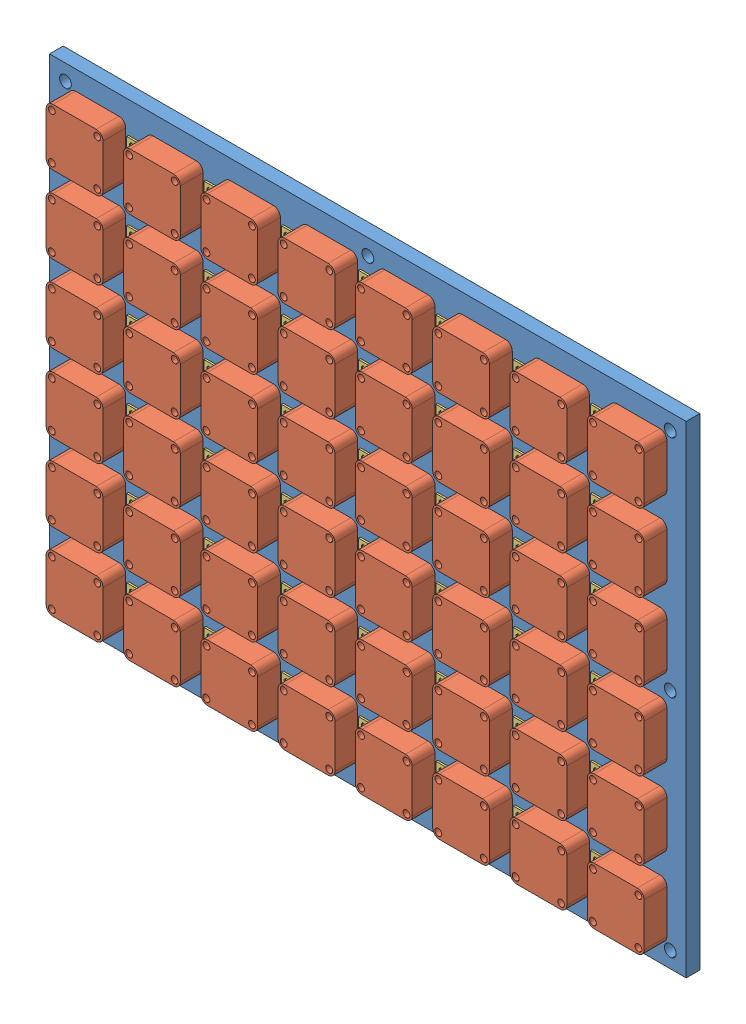
SolidWorks assembly plate_assembly, configuration Default. Lengths in mm.
Overall size (280 212 16.95).
134 component instances, 4 part files, 11 mates.
Components (placement in the parent):
- plate-1: plate [Default] at (3.9208 5.1033 -0.2161) size (280 212 6)
- Fan-1: Fan [Default] at (-115.0792 40.1033 15.7839) size (25 25 10)
- XHP-2-1: XHP-2 [Default] at (-101.3792 93.7533 2.7139) x (0 1 0) z (1 0 0) size (7.3 7.75 5.7)
- XHP-2-2: XHP-2 [Default] at (-101.3792 86.4533 2.7139) x (0 1 0) z (1 0 0) size (7.3 7.75 5.7)
- Fan-2: Fan [Default] at (-115.0792 74.1033 15.7839) size (25 25 10)
- Fan-3: Fan [Default] at (-115.0792 108.1033 15.7839) size (25 25 10)
- Fan-4: Fan [Default] at (-115.0792 142.1033 15.7839) size (25 25 10)
- Fan-5: Fan [Default] at (-115.0792 176.1033 15.7839) size (25 25 10)
- Fan-6: Fan [Default] at (-115.0792 210.1033 15.7839) size (25 25 10)
- Fan-7: Fan [Default] at (-81.0792 40.1033 15.7839) size (25 25 10)
- Fan-8: Fan [Default] at (-81.0792 74.1033 15.7839) size (25 25 10)
- Fan-9: Fan [Default] at (-81.0792 108.1033 15.7839) size (25 25 10)
- Fan-10: Fan [Default] at (-81.0792 142.1033 15.7839) size (25 25 10)
- Fan-11: Fan [Default] at (-81.0792 176.1033 15.7839) size (25 25 10)
- Fan-12: Fan [Default] at (-81.0792 210.1033 15.7839) size (25 25 10)
- Fan-13: Fan [Default] at (-47.0792 40.1033 15.7839) size (25 25 10)
- Fan-14: Fan [Default] at (-47.0792 74.1033 15.7839) size (25 25 10)
- Fan-15: Fan [Default] at (-47.0792 108.1033 15.7839) size (25 25 10)
- Fan-16: Fan [Default] at (-47.0792 142.1033 15.7839) size (25 25 10)
- Fan-17: Fan [Default] at (-47.0792 176.1033 15.7839) size (25 25 10)
- Fan-18: Fan [Default] at (-47.0792 210.1033 15.7839) size (25 25 10)
- Fan-19: Fan [Default] at (-13.0792 40.1033 15.7839) size (25 25 10)
- Fan-20: Fan [Default] at (-13.0792 74.1033 15.7839) size (25 25 10)
- Fan-21: Fan [Default] at (-13.0792 108.1033 15.7839) size (25 25 10)
- Fan-22: Fan [Default] at (-13.0792 142.1033 15.7839) size (25 25 10)
- Fan-23: Fan [Default] at (-13.0792 176.1033 15.7839) size (25 25 10)
- Fan-24: Fan [Default] at (-13.0792 210.1033 15.7839) size (25 25 10)
- Fan-25: Fan [Default] at (20.9208 40.1033 15.7839) size (25 25 10)
- Fan-26: Fan [Default] at (20.9208 74.1033 15.7839) size (25 25 10)
- Fan-27: Fan [Default] at (20.9208 108.1033 15.7839) size (25 25 10)
- Fan-28: Fan [Default] at (20.9208 142.1033 15.7839) size (25 25 10)
- Fan-29: Fan [Default] at (20.9208 176.1033 15.7839) size (25 25 10)
- Fan-30: Fan [Default] at (20.9208 210.1033 15.7839) size (25 25 10)
- Fan-31: Fan [Default] at (54.9208 40.1033 15.7839) size (25 25 10)
- Fan-32: Fan [Default] at (54.9208 74.1033 15.7839) size (25 25 10)
- Fan-33: Fan [Default] at (54.9208 108.1033 15.7839) size (25 25 10)
- Fan-34: Fan [Default] at (54.9208 142.1033 15.7839) size (25 25 10)
- Fan-35: Fan [Default] at (54.9208 176.1033 15.7839) size (25 25 10)
- Fan-36: Fan [Default] at (54.9208 210.1033 15.7839) size (25 25 10)
- Fan-37: Fan [Default] at (88.9208 40.1033 15.7839) size (25 25 10)
- Fan-38: Fan [Default] at (88.9208 74.1033 15.7839) size (25 25 10)
- Fan-39: Fan [Default] at (88.9208 108.1033 15.7839) size (25 25 10)
- Fan-40: Fan [Default] at (88.9208 142.1033 15.7839) size (25 25 10)
- Fan-41: Fan [Default] at (88.9208 176.1033 15.7839) size (25 25 10)
- Fan-42: Fan [Default] at (88.9208 210.1033 15.7839) size (25 25 10)
- Fan-43: Fan [Default] at (122.9208 40.1033 15.7839) size (25 25 10)
- Fan-44: Fan [Default] at (122.9208 74.1033 15.7839) size (25 25 10)
- Fan-45: Fan [Default] at (122.9208 108.1033 15.7839) size (25 25 10)
- Fan-46: Fan [Default] at (122.9208 142.1033 15.7839) size (25 25 10)
- Fan-47: Fan [Default] at (122.9208 176.1033 15.7839) size (25 25 10)
- Fan-48: Fan [Default] at (122.9208 210.1033 15.7839) size (25 25 10)
- Board^plate_assembly-1: Board^plate_assembly [Default] at (-14.5259 93.2281 -1.2161) (suppressed, hidden, virtual)
- XHP-2-3: XHP-2 [Default] at (-67.3792 86.4533 2.7139) x (0 1 0) z (1 0 0) size (7.3 7.75 5.7)
- XHP-2-4: XHP-2 [Default] at (-33.3792 86.4533 2.7139) x (0 1 0) z (1 0 0) size (7.3 7.75 5.7)
- XHP-2-5: XHP-2 [Default] at (0.6208 86.4533 2.7139) x (0 1 0) z (1 0 0) size (7.3 7.75 5.7)
- XHP-2-6: XHP-2 [Default] at (34.6208 86.4533 2.7139) x (0 1 0) z (1 0 0) size (7.3 7.75 5.7)
- XHP-2-7: XHP-2 [Default] at (68.6208 86.4533 2.7139) x (0 1 0) z (1 0 0) size (7.3 7.75 5.7)
- XHP-2-8: XHP-2 [Default] at (102.6208 86.4533 2.7139) x (0 1 0) z (1 0 0) size (7.3 7.75 5.7)
- XHP-2-9: XHP-2 [Default] at (-101.3792 52.4533 2.7139) x (0 1 0) z (1 0 0) size (7.3 7.75 5.7)
- XHP-2-10: XHP-2 [Default] at (-67.3792 52.4533 2.7139) x (0 1 0) z (1 0 0) size (7.3 7.75 5.7)
- XHP-2-11: XHP-2 [Default] at (-33.3792 52.4533 2.7139) x (0 1 0) z (1 0 0) size (7.3 7.75 5.7)
- XHP-2-12: XHP-2 [Default] at (0.6208 52.4533 2.7139) x (0 1 0) z (1 0 0) size (7.3 7.75 5.7)
- XHP-2-13: XHP-2 [Default] at (34.6208 52.4533 2.7139) x (0 1 0) z (1 0 0) size (7.3 7.75 5.7)
- XHP-2-14: XHP-2 [Default] at (68.6208 52.4533 2.7139) x (0 1 0) z (1 0 0) size (7.3 7.75 5.7)
- XHP-2-15: XHP-2 [Default] at (102.6208 52.4533 2.7139) x (0 1 0) z (1 0 0) size (7.3 7.75 5.7)
- XHP-2-16: XHP-2 [Default] at (-101.3792 18.4533 2.7139) x (0 1 0) z (1 0 0) size (7.3 7.75 5.7)
- XHP-2-17: XHP-2 [Default] at (-67.3792 18.4533 2.7139) x (0 1 0) z (1 0 0) size (7.3 7.75 5.7)
- XHP-2-18: XHP-2 [Default] at (-33.3792 18.4533 2.7139) x (0 1 0) z (1 0 0) size (7.3 7.75 5.7)
- XHP-2-19: XHP-2 [Default] at (0.6208 18.4533 2.7139) x (0 1 0) z (1 0 0) size (7.3 7.75 5.7)
- XHP-2-20: XHP-2 [Default] at (34.6208 18.4533 2.7139) x (0 1 0) z (1 0 0) size (7.3 7.75 5.7)
- XHP-2-21: XHP-2 [Default] at (68.6208 18.4533 2.7139) x (0 1 0) z (1 0 0) size (7.3 7.75 5.7)
- XHP-2-22: XHP-2 [Default] at (102.6208 18.4533 2.7139) x (0 1 0) z (1 0 0) size (7.3 7.75 5.7)
- XHP-2-23: XHP-2 [Default] at (-101.3792 -15.5467 2.7139) x (0 1 0) z (1 0 0) size (7.3 7.75 5.7)
- XHP-2-24: XHP-2 [Default] at (-67.3792 -15.5467 2.7139) x (0 1 0) z (1 0 0) size (7.3 7.75 5.7)
- XHP-2-25: XHP-2 [Default] at (-33.3792 -15.5467 2.7139) x (0 1 0) z (1 0 0) size (7.3 7.75 5.7)
- XHP-2-26: XHP-2 [Default] at (0.6208 -15.5467 2.7139) x (0 1 0) z (1 0 0) size (7.3 7.75 5.7)
- XHP-2-27: XHP-2 [Default] at (34.6208 -15.5467 2.7139) x (0 1 0) z (1 0 0) size (7.3 7.75 5.7)
- XHP-2-28: XHP-2 [Default] at (68.6208 -15.5467 2.7139) x (0 1 0) z (1 0 0) size (7.3 7.75 5.7)
- XHP-2-29: XHP-2 [Default] at (102.6208 -15.5467 2.7139) x (0 1 0) z (1 0 0) size (7.3 7.75 5.7)
- XHP-2-30: XHP-2 [Default] at (-101.3792 -49.5467 2.7139) x (0 1 0) z (1 0 0) size (7.3 7.75 5.7)
- XHP-2-31: XHP-2 [Default] at (-67.3792 -49.5467 2.7139) x (0 1 0) z (1 0 0) size (7.3 7.75 5.7)
- XHP-2-32: XHP-2 [Default] at (-33.3792 -49.5467 2.7139) x (0 1 0) z (1 0 0) size (7.3 7.75 5.7)
- XHP-2-33: XHP-2 [Default] at (0.6208 -49.5467 2.7139) x (0 1 0) z (1 0 0) size (7.3 7.75 5.7)
- XHP-2-34: XHP-2 [Default] at (34.6208 -49.5467 2.7139) x (0 1 0) z (1 0 0) size (7.3 7.75 5.7)
- XHP-2-35: XHP-2 [Default] at (68.6208 -49.5467 2.7139) x (0 1 0) z (1 0 0) size (7.3 7.75 5.7)
- XHP-2-36: XHP-2 [Default] at (102.6208 -49.5467 2.7139) x (0 1 0) z (1 0 0) size (7.3 7.75 5.7)
- XHP-2-37: XHP-2 [Default] at (-101.3792 -83.5467 2.7139) x (0 1 0) z (1 0 0) size (7.3 7.75 5.7)
- XHP-2-38: XHP-2 [Default] at (-67.3792 -83.5467 2.7139) x (0 1 0) z (1 0 0) size (7.3 7.75 5.7)
- XHP-2-39: XHP-2 [Default] at (-33.3792 -83.5467 2.7139) x (0 1 0) z (1 0 0) size (7.3 7.75 5.7)
- XHP-2-40: XHP-2 [Default] at (0.6208 -83.5467 2.7139) x (0 1 0) z (1 0 0) size (7.3 7.75 5.7)
- XHP-2-41: XHP-2 [Default] at (34.6208 -83.5467 2.7139) x (0 1 0) z (1 0 0) size (7.3 7.75 5.7)
- XHP-2-42: XHP-2 [Default] at (68.6208 -83.5467 2.7139) x (0 1 0) z (1 0 0) size (7.3 7.75 5.7)
- XHP-2-43: XHP-2 [Default] at (102.6208 -83.5467 2.7139) x (0 1 0) z (1 0 0) size (7.3 7.75 5.7)
- XHP-2-44: XHP-2 [Default] at (-67.3792 93.7533 2.7139) x (0 1 0) z (1 0 0) size (7.3 7.75 5.7)
- XHP-2-45: XHP-2 [Default] at (-33.3792 93.7533 2.7139) x (0 1 0) z (1 0 0) size (7.3 7.75 5.7)
- XHP-2-46: XHP-2 [Default] at (0.6208 93.7533 2.7139) x (0 1 0) z (1 0 0) size (7.3 7.75 5.7)
- XHP-2-47: XHP-2 [Default] at (34.6208 93.7533 2.7139) x (0 1 0) z (1 0 0) size (7.3 7.75 5.7)
- XHP-2-48: XHP-2 [Default] at (68.6208 93.7533 2.7139) x (0 1 0) z (1 0 0) size (7.3 7.75 5.7)
- XHP-2-49: XHP-2 [Default] at (102.6208 93.7533 2.7139) x (0 1 0) z (1 0 0) size (7.3 7.75 5.7)
- XHP-2-50: XHP-2 [Default] at (-101.3792 59.7533 2.7139) x (0 1 0) z (1 0 0) size (7.3 7.75 5.7)
- XHP-2-51: XHP-2 [Default] at (-67.3792 59.7533 2.7139) x (0 1 0) z (1 0 0) size (7.3 7.75 5.7)
- XHP-2-52: XHP-2 [Default] at (-33.3792 59.7533 2.7139) x (0 1 0) z (1 0 0) size (7.3 7.75 5.7)
- XHP-2-53: XHP-2 [Default] at (0.6208 59.7533 2.7139) x (0 1 0) z (1 0 0) size (7.3 7.75 5.7)
- XHP-2-54: XHP-2 [Default] at (34.6208 59.7533 2.7139) x (0 1 0) z (1 0 0) size (7.3 7.75 5.7)
- XHP-2-55: XHP-2 [Default] at (68.6208 59.7533 2.7139) x (0 1 0) z (1 0 0) size (7.3 7.75 5.7)
- XHP-2-56: XHP-2 [Default] at (102.6208 59.7533 2.7139) x (0 1 0) z (1 0 0) size (7.3 7.75 5.7)
- XHP-2-57: XHP-2 [Default] at (-101.3792 25.7533 2.7139) x (0 1 0) z (1 0 0) size (7.3 7.75 5.7)
- XHP-2-58: XHP-2 [Default] at (-67.3792 25.7533 2.7139) x (0 1 0) z (1 0 0) size (7.3 7.75 5.7)
- XHP-2-59: XHP-2 [Default] at (-33.3792 25.7533 2.7139) x (0 1 0) z (1 0 0) size (7.3 7.75 5.7)
- XHP-2-60: XHP-2 [Default] at (0.6208 25.7533 2.7139) x (0 1 0) z (1 0 0) size (7.3 7.75 5.7)
- XHP-2-61: XHP-2 [Default] at (34.6208 25.7533 2.7139) x (0 1 0) z (1 0 0) size (7.3 7.75 5.7)
- XHP-2-62: XHP-2 [Default] at (68.6208 25.7533 2.7139) x (0 1 0) z (1 0 0) size (7.3 7.75 5.7)
- XHP-2-63: XHP-2 [Default] at (102.6208 25.7533 2.7139) x (0 1 0) z (1 0 0) size (7.3 7.75 5.7)
- XHP-2-64: XHP-2 [Default] at (-101.3792 -8.2467 2.7139) x (0 1 0) z (1 0 0) size (7.3 7.75 5.7)
- XHP-2-65: XHP-2 [Default] at (-67.3792 -8.2467 2.7139) x (0 1 0) z (1 0 0) size (7.3 7.75 5.7)
- XHP-2-66: XHP-2 [Default] at (-33.3792 -8.2467 2.7139) x (0 1 0) z (1 0 0) size (7.3 7.75 5.7)
- XHP-2-67: XHP-2 [Default] at (0.6208 -8.2467 2.7139) x (0 1 0) z (1 0 0) size (7.3 7.75 5.7)
- XHP-2-68: XHP-2 [Default] at (34.6208 -8.2467 2.7139) x (0 1 0) z (1 0 0) size (7.3 7.75 5.7)
- XHP-2-69: XHP-2 [Default] at (68.6208 -8.2467 2.7139) x (0 1 0) z (1 0 0) size (7.3 7.75 5.7)
- XHP-2-70: XHP-2 [Default] at (102.6208 -8.2467 2.7139) x (0 1 0) z (1 0 0) size (7.3 7.75 5.7)
- XHP-2-71: XHP-2 [Default] at (-101.3792 -42.2467 2.7139) x (0 1 0) z (1 0 0) size (7.3 7.75 5.7)
- XHP-2-72: XHP-2 [Default] at (-67.3792 -42.2467 2.7139) x (0 1 0) z (1 0 0) size (7.3 7.75 5.7)
- XHP-2-73: XHP-2 [Default] at (-33.3792 -42.2467 2.7139) x (0 1 0) z (1 0 0) size (7.3 7.75 5.7)
- XHP-2-74: XHP-2 [Default] at (0.6208 -42.2467 2.7139) x (0 1 0) z (1 0 0) size (7.3 7.75 5.7)
- XHP-2-75: XHP-2 [Default] at (34.6208 -42.2467 2.7139) x (0 1 0) z (1 0 0) size (7.3 7.75 5.7)
- XHP-2-76: XHP-2 [Default] at (68.6208 -42.2467 2.7139) x (0 1 0) z (1 0 0) size (7.3 7.75 5.7)
- XHP-2-77: XHP-2 [Default] at (102.6208 -42.2467 2.7139) x (0 1 0) z (1 0 0) size (7.3 7.75 5.7)
- XHP-2-78: XHP-2 [Default] at (-101.3792 -76.2467 2.7139) x (0 1 0) z (1 0 0) size (7.3 7.75 5.7)
- XHP-2-79: XHP-2 [Default] at (-67.3792 -76.2467 2.7139) x (0 1 0) z (1 0 0) size (7.3 7.75 5.7)
- XHP-2-80: XHP-2 [Default] at (-33.3792 -76.2467 2.7139) x (0 1 0) z (1 0 0) size (7.3 7.75 5.7)
- XHP-2-81: XHP-2 [Default] at (0.6208 -76.2467 2.7139) x (0 1 0) z (1 0 0) size (7.3 7.75 5.7)
- XHP-2-82: XHP-2 [Default] at (34.6208 -76.2467 2.7139) x (0 1 0) z (1 0 0) size (7.3 7.75 5.7)
- XHP-2-83: XHP-2 [Default] at (68.6208 -76.2467 2.7139) x (0 1 0) z (1 0 0) size (7.3 7.75 5.7)
- XHP-2-84: XHP-2 [Default] at (102.6208 -76.2467 2.7139) x (0 1 0) z (1 0 0) size (7.3 7.75 5.7)
Mates (geometry in assembly coordinates):
- Coincident1: coincident anti-aligned: plane of plate-1 through (73.9208 -266.8967 5.7839) normal (0 0 1); plane of Fan-1 through (-124.5792 -89.3967 5.7839) normal (0 0 -1)
- Concentric1: concentric anti-aligned: cylinder of plate-1 through (-125.0792 -69.8967 5.7839) axis (0 0 -1) radius 1.6; cylinder of Fan-1 through (-125.0792 -69.8967 5.7839) axis (0 0 1) radius 1.5
- Concentric2: concentric anti-aligned: cylinder of plate-1 through (-105.0792 -89.8967 5.7839) axis (0 0 -1) radius 1.6; cylinder of Fan-1 through (-105.0792 -89.8967 5.7839) axis (0 0 1) radius 1.5
- Coincident2: coincident: plane of plate-1 through (73.9208 -266.8967 -0.2161) normal (0 0 -1); plane of Board^plate_assembly-1 through (-14.5259 93.2281 -0.2161) normal (0 0 1)
- Coincident3: coincident anti-aligned: plane of plate-1 through (73.9208 -266.8967 5.7839) normal (0 0 1); plane of XHP-2-1 through (-100.5792 90.1033 5.7839) normal (0 0 -1)
- Coincident4: coincident anti-aligned: plane of plate-1 through (3.2939 96.6033 5.7839) normal (0 -1 0); plane of XHP-2-1 through (-100.5792 96.6033 6.5839) normal (0 1 0)
- Coincident5: coincident anti-aligned: plane of plate-1 through (-100.5792 93.5001 5.7839) normal (1 0 0); plane of XHP-2-1 through (-100.5792 90.9033 -1.1661) normal (-1 0 0)
- Coincident6: coincident anti-aligned: plane of plate-1 through (-100.5792 93.5001 5.7839) normal (1 0 0); plane of XHP-2-2 through (-100.5792 83.6033 -1.1661) normal (-1 0 0)
- Coincident7: coincident anti-aligned: plane of plate-1 through (3.9208 83.6033 5.7839) normal (0 1 0); plane of XHP-2-2 through (-100.5792 83.6033 6.5839) normal (0 -1 0)
- Coincident8: coincident anti-aligned: plane of plate-1 through (73.9208 -266.8967 5.7839) normal (0 0 1); plane of XHP-2-2 through (-100.5792 82.8033 5.7839) normal (0 0 -1)
- Coincident9: coincident anti-aligned: plane of plate-1 through (73.9208 -266.8967 -0.2161) normal (0 0 -1); plane of Board^plate_assembly-1 through (-14.5259 93.2281 -0.2161) normal (0 0 1)
